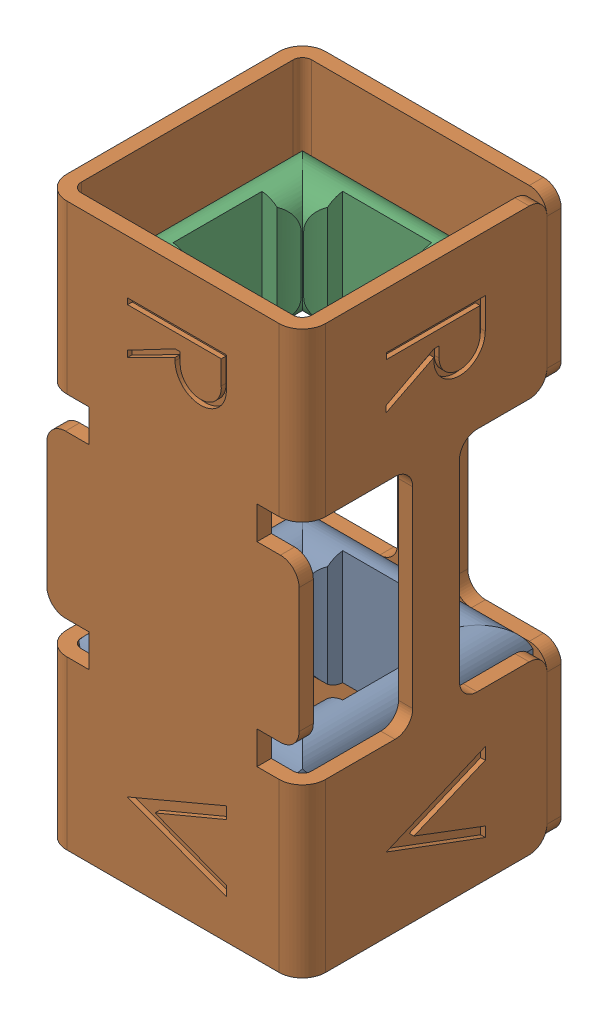
SolidWorks assembly 02914-3-0000_BENT, configuration Default. Lengths in mm.
Overall size (2.77 6.02 2.77).
3 component instances, 2 part files, 0 mates.
Components (placement in the parent):
- 02559-0-0000_WRAPPED-1: 02559-0-0000_WRAPPED [Default] at (-46.7822 8.4293 -2.5496) x (0 1 0) z (0 0 1) size (1.23 2.47 2.48)
- 02915-0-0000_Correct Wrap-1: 02915-0-0000_Correct Wrap [Default] at (-56.4542 13.0993 2.6363) x (1 0 0) z (0 0 -1) size (2.77 6.02 2.77)
- 02559-0-0000_WRAPPED-2: 02559-0-0000_WRAPPED [Default] at (-46.7822 11.7593 -2.5496) x (0 1 0) z (0 0 1) size (1.23 2.47 2.48)
